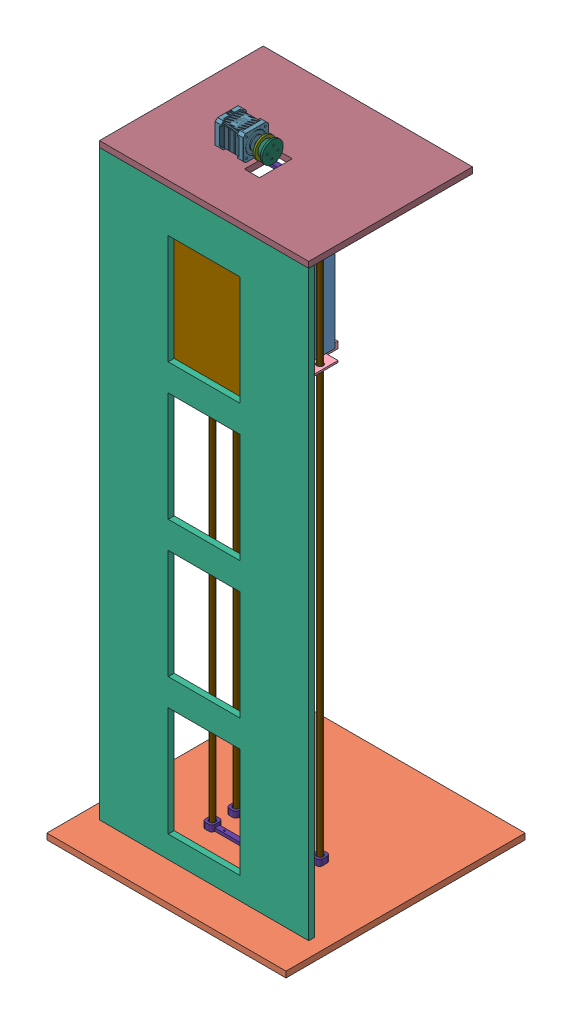
SolidWorks assembly Assembly, configuration Default. Lengths in mm.
Overall size (400 1036.9 400).
23 component instances, 18 part files, 57 mates.
Components (placement in the parent):
- Cabin-1: Cabin [Default] at (150 731 188) size (120 180 120)
- Ground-1: Ground [Default] at (150 0 150) size (400 10 400)
- Mini Stepper Motor-1: Mini Stepper Motor [Default] at (113 929 241) x (-1 0 0) z (0 0 1) size (42 31 29)
- Door Tray-1: Door Tray [Default] at (150 728 194.5) size (160 11 138)
- Mini Stepper Bed-1: Mini Stepper Bed [Default] at (90 911 218) size (45 34 24)
- Outer Wall-1-1: Outer Wall-1 [Default] at (-20 10 277) size (350 974 10)
- Door Tray-Outer-1: Door Tray-Outer [Default] at (150 728 332.5) x (-1 0 0) z (0 0 -1) size (242 11 36)
- Two Pin Door-2: Two Pin Door [Default] at (150 821 253) x (-1 0 0) z (0 0 -1) size (120 176.5 19)
- One Pin Door-1: One Pin Door [Default] at (150 821 272) size (120 180 19)
- Door Gear-1: Door Gear [Default] at (228.1634 1126.1729 189.2665) x (0 -1 0) z (0 0 1) size (17.77 17.77 8)
- Rack-1: Rack [Default] at (110.0588 887.4412 248) size (188.5 7.01 5)
- Door Tray-Outer-Top-1: Door Tray-Outer-Top [Default] at (150 917 332.5) x (-1 0 0) z (0 0 -1) size (242 11 36)
- Top-1: Top [Default] at (150 984 188) size (350 10 274)
- NEMA-17-2: NEMA-17 [Varsayılan] at (82.5 1027.6804 169.0755) x (0 0 1) z (1 0 0) size (42.33 42.92 73.02)
- Sheave Assembly-1: Sheave Assembly [Default] at (172.5272 987.3378 191.9878) x (0 -0.152539 -0.988298) z (0 0.988298 -0.152539) size (35.4 24 35.4)
  - Sheave-1-1: Sheave-1 [Default] at (7.7534 18.0272 29.3382) size (35.4 12 35.4)
  - Sheave-2-1: Sheave-2 [Default] at (7.7534 27.0272 29.3382) x (-1 0 0) z (0 0 -1) size (35.4 12 35.4)
- Rail Holder-1: Rail Holder [Default] at (72 984 194) x (1 0 0) z (0 0 -1) size (156 10 58)
- Rail Holder-2: Rail Holder [Default] at (72 10 172) size (156 10 58)
- Rail-1: Rail [Default] at (220 10 203) x (0.993509 0 -0.113752) z (0.113752 0 0.993509) size (8 974 8)
- Rail-2: Rail [Default] at (80 10 203) x (0.859284 0 -0.5115) z (0.5115 0 0.859284) size (8 974 8)
- Rail-3: Rail [Default] at (80 10 163) x (-0.13836 0 0.990382) z (-0.990382 0 -0.13836) size (8 974 8)
- Rail-4: Rail [Default] at (220 10 163) x (0.893367 0 -0.449328) z (0.449328 0 0.893367) size (8 974 8)
Mates (geometry in assembly coordinates):
- Width8: width anti-aligned: plane of Cabin-1 through (210 911 248) normal (1 0 0); plane of Ground-1 through (90 911 248) normal (-1 0 0); plane of Cabin-1 through (-50 10 350) normal (-1 0 0); plane of Ground-1 through (350 10 350) normal (1 0 0)
- Coincident44: coincident anti-aligned: plane of Cabin-1 through (150 731 188) normal (0 -1 0); plane of Door Tray-1 through (150 731 194.5) normal (0 1 0)
- Coincident48: coincident aligned: plane of Cabin-1 through (210 911 248) normal (1 0 0); plane of Door Tray-1 through (210 731 261) normal (1 0 0)
- Coincident49: coincident anti-aligned: plane of Cabin-1 through (90 911 128) normal (0 0 -1); plane of Door Tray-1 through (90 739 128) normal (0 0 1)
- Coincident50: coincident anti-aligned: plane of Mini Stepper Motor-1 through (113 929 222) normal (0 0 -1); plane of Mini Stepper Bed-1 through (90 911 222) normal (0 0 1)
- Distance5: distance = 2 mm: line of Mini Stepper Motor-1 through (92 929 241) axis (0 0 -1); plane of Mini Stepper Bed-1 through (90 945 222) normal (-1 0 0)
- Parallel2: parallel aligned: plane of Mini Stepper Motor-1 through (120 946 224.5) normal (0 1 0); plane of Mini Stepper Bed-1 through (90 945 222) normal (0 1 0)
- Tangent2: tangent anti-aligned: cylinder of Mini Stepper Motor-1 through (113 929 241) axis (0 0 -1) radius 14; plane of Mini Stepper Bed-1 through (90 915 242) normal (0 1 0)
- Distance8: distance = 0 mm aligned: plane of Mini Stepper Bed-1 through (90 945 222) normal (-1 0 0); plane of Cabin-1 through (90 911 248) normal (-1 0 0)
- Coincident56: coincident aligned: plane of Door Gear-1 through (228.1634 1126.1729 253) normal (0 0 1); plane of Rack-1 through (90 914.5063 253) normal (0 0 1)
- Coincident64: coincident anti-aligned: plane of Ground-1 through (150 10 150) normal (0 1 0); plane of Outer Wall-1-1 through (-20 10 287) normal (0 -1 0)
- Coincident109: coincident anti-aligned: plane of Cabin-1 through (210 911 248) normal (1 0 0); plane of Outer Wall-1-1 through (210 47 287) normal (-1 0 0)
- Coincident75: coincident anti-aligned: plane of Outer Wall-1-1 through (-20 10 277) normal (0 0 -1); plane of Door Tray-Outer-1 through (210 728 277) normal (0 0 1)
- Coincident76: coincident aligned: plane of Outer Wall-1-1 through (90 731 287) normal (0 1 0); plane of Door Tray-Outer-1 through (150 731 332.5) normal (0 1 0)
- Parallel3: parallel anti-aligned: plane of Cabin-1 through (90 911 248) normal (0 0 1); plane of Two Pin Door-2 through (150 821 248) normal (0 0 -1)
- Coincident79: coincident aligned: plane of Cabin-1 through (150 731 188) normal (0 -1 0); plane of Two Pin Door-2 through (210 731 248) normal (0 -1 0)
- Coincident80: coincident anti-aligned: plane of Cabin-1 through (90 911 248) normal (0 0 1); plane of Two Pin Door-2 through (150 821 248) normal (0 0 -1)
- LimitDistance2: limit distance = 0 mm aligned: plane of Cabin-1 through (210 911 248) normal (1 0 0); plane of Two Pin Door-2 through (210 731 248) normal (1 0 0)
- Coincident82: coincident anti-aligned: plane of Cabin-1 through (150 911 188) normal (0 1 0); plane of Mini Stepper Bed-1 through (90 911 222) normal (0 -1 0)
- Coincident83: coincident anti-aligned: plane of Outer Wall-1-1 through (-20 10 277) normal (0 0 -1); plane of One Pin Door-1 through (150 821 277) normal (0 0 1)
- Width9: width anti-aligned: plane of Two Pin Door-2 through (143 891 267) normal (1 0 0); plane of One Pin Door-1 through (157 891 267) normal (-1 0 0); plane of Two Pin Door-2 through (146 751 258) normal (-1 0 0); plane of One Pin Door-1 through (154 751 258) normal (1 0 0)
- Coincident86: coincident anti-aligned: plane of One Pin Door-1 through (90 731 277) normal (0 -1 0); plane of Door Tray-Outer-1 through (150 731 332.5) normal (0 1 0)
- Distance7: distance = 3 mm anti-aligned: plane of Door Tray-Outer-1 through (210 731 264) normal (0 0 -1); plane of Door Tray-1 through (90 731 261) normal (0 0 1)
- Parallel5: parallel anti-aligned: plane of Mini Stepper Motor-1 through (113 929 241) normal (0 0 1); plane of Door Gear-1 through (228.1634 1126.1729 245) normal (0 0 -1)
- Coincident96: coincident anti-aligned: line of Mini Stepper Motor-1 through (115 923.5 245) axis (-1 0 0); line of Door Gear-1 through (110.9287 923.5 245) axis (1 0 0)
- Lock1: lock: unknown of Mini Stepper Motor-1; unknown of Door Gear-1
- Coincident101: coincident anti-aligned: plane of Two Pin Door-2 through (90 907.5 243) normal (0 1 0); plane of Rack-1 through (184.2478 907.5 248) normal (0 -1 0)
- Coincident102: coincident aligned: plane of Rack-1 through (90 914.5063 248) normal (-1 0 0); plane of Two Pin Door-2 through (90 731 248) normal (-1 0 0)
- Coincident103: coincident aligned: plane of Two Pin Door-2 through (150 821 248) normal (0 0 -1); plane of Rack-1 through (184.2478 914.5063 248) normal (0 0 -1)
- Distance10: distance = 7 mm anti-aligned: plane of Outer Wall-1-1 through (210 731 287) normal (-1 0 0); plane of Door Tray-Outer-1 through (217 728 332.5) normal (1 0 0)
- Distance11: distance = 7 mm anti-aligned: plane of Outer Wall-1-1 through (210 731 287) normal (-1 0 0); plane of Door Tray-Outer-Top-1 through (217 917 332.5) normal (1 0 0)
- Coincident106: coincident aligned: plane of Outer Wall-1-1 through (90 914 287) normal (0 -1 0); plane of Door Tray-Outer-Top-1 through (150 914 332.5) normal (0 -1 0)
- Coincident107: coincident anti-aligned: plane of Outer Wall-1-1 through (-20 10 277) normal (0 0 -1); plane of Door Tray-Outer-Top-1 through (210 917 277) normal (0 0 1)
- Coincident110: coincident aligned: plane of Outer Wall-1-1 through (-20 10 287) normal (0 0 1); plane of Top-1 through (-25 984 287) normal (0 0 1)
- Coincident111: coincident anti-aligned: plane of Outer Wall-1-1 through (-20 984 287) normal (0 1 0); plane of Top-1 through (150 984 188) normal (0 -1 0)
- Coincident112: coincident aligned: plane of Outer Wall-1-1 through (-25 10 287) normal (-1 0 0); plane of Top-1 through (-25 994 363) normal (-1 0 0)
- Coincident113: coincident anti-aligned: plane of Top-1 through (150 994 188) normal (0 1 0); plane of NEMA-17-2 through (129.5 994 158.7) normal (0 -1 0)
- Concentric1: concentric anti-aligned: circle of NEMA-17-2; cylinder of Sheave Assembly-1/Sheave-2-1 through (145.5 1015.15 179.85) axis (-1 0 0) radius 3.1
- Distance12: distance = 2 mm anti-aligned: plane of Sheave Assembly-1/Sheave-2-1 through (133.5 1015.15 179.85) normal (-1 0 0); plane of NEMA-17-2 through (131.5 1015.15 179.85) normal (1 0 0)
- Distance13: distance = 5 mm anti-aligned: plane of Sheave Assembly-1/Sheave-1-1 through (157.5 1015.15 179.85) normal (1 0 0); plane of Top-1 through (162.5 984 152) normal (-1 0 0)
- Distance14: distance = 6 mm anti-aligned: plane of NEMA-17-2 through (129.5 1036.3 201) normal (0 0 1); plane of Top-1 through (137.5 984 207) normal (0 0 -1)
- Distance15: distance = 63 mm aligned: plane of Outer Wall-1-1 through (-20 10 287) normal (0 0 1); plane of Ground-1 through (-50 10 350) normal (0 0 1)
- LimitDistance3: limit distance = 718 mm anti-aligned: plane of Ground-1 through (150 10 150) normal (0 1 0); plane of Door Tray-1 through (150 728 194.5) normal (0 -1 0)
- Coincident114: coincident anti-aligned: plane of Top-1 through (150 984 188) normal (0 -1 0); plane of Rail Holder-1 through (72 984 194) normal (0 1 0)
- Concentric2: concentric aligned: cylinder of Door Tray-1 through (80 651 203) axis (0 1 0) radius 5.5; cylinder of Rail Holder-1 through (80 974 203) axis (0 1 0) radius 5.2
- Concentric3: concentric aligned: cylinder of Door Tray-1 through (220 651 163) axis (0 1 0) radius 5.5; cylinder of Rail Holder-1 through (220 974 163) axis (0 1 0) radius 5.2
- Coincident115: coincident anti-aligned: plane of Ground-1 through (150 10 150) normal (0 1 0); plane of Rail Holder-2 through (72 10 172) normal (0 -1 0)
- Concentric4: concentric anti-aligned: circle of Door Tray-1; cylinder of Rail Holder-2 through (220 20 163) axis (0 -1 0) radius 5.2
- Concentric5: concentric anti-aligned: cylinder of Door Tray-1 through (80 651 163) axis (0 1 0) radius 5.5; cylinder of Rail Holder-2 through (80 20 163) axis (0 -1 0) radius 5.2
- Concentric6: concentric anti-aligned: circle of Rail Holder-1; circle of Rail-1
- Concentric7: concentric anti-aligned: circle of Rail Holder-1; circle of Rail-4
- Concentric8: concentric anti-aligned: circle of Rail Holder-1; circle of Rail-3
- Concentric9: concentric anti-aligned: circle of Rail Holder-1; circle of Rail-2
- Coincident121: coincident aligned: plane of Ground-1 through (150 10 150) normal (0 1 0); circle of Rail-1
- Coincident122: coincident aligned: plane of Ground-1 through (150 10 150) normal (0 1 0); circle of Rail-4
- Coincident123: coincident aligned: plane of Ground-1 through (150 10 150) normal (0 1 0); circle of Rail-2
- Coincident124: coincident aligned: plane of Ground-1 through (150 10 150) normal (0 1 0); circle of Rail-3
